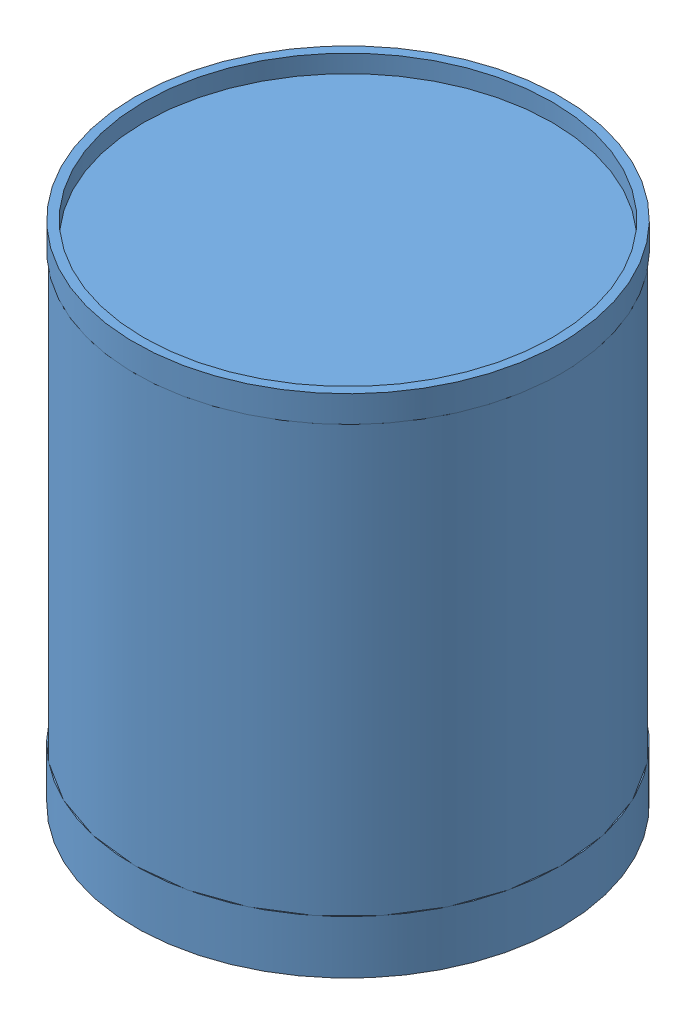
SolidWorks assembly ConceptAssem_2, configuration Free. Lengths in mm.
Overall size (1219.2 1447.8 1219.2).
21 component instances, 5 part files, 67 mates.
Components (placement in the parent):
- Case-1: Case [Default] x (1 0 0) z (0 1 0)
- RotatingStand-1: RotatingStand [Default] at (0 25.4 0) x (1 0 0) z (0 1 0)
- TopSpin_Lower-1: TopSpin_Lower [Default] at (0 152.4 0) x (0.999984 0 -0.005596) z (0 1 0)
- TopSpin_Upper-1: TopSpin_Upper [Default] at (0 266.7 57.1491) x (0.996384 0 0.084968) z (0 1 0)
- SlotGuide-1: SlotGuide [Default] at (0 254 -4.0566) x (-1 0 0) z (0 -1 0)
- SlotGuide-3: SlotGuide [Default] at (0 358.4222 52.8867) x (-1 0 0) z (0 -1 0)
- TopSpin_Upper-3: TopSpin_Upper [Default] at (0 371.1222 114.0924) x (0.999041 0 0.043775) z (0 1 0)
- TopSpin_Upper-5: TopSpin_Upper [Default] at (0 475.5444 171.1877) x (0.998053 0 0.062371) z (0 1 0)
- SlotGuide-5: SlotGuide [Default] at (0 462.8444 109.9819) x (-1 0 0) z (0 -1 0)
- TopSpin_Upper-6: TopSpin_Upper [Default] at (0 579.9667 228.2264) x (0.999167 0 0.040797) z (0 1 0)
- SlotGuide-6: SlotGuide [Default] at (0 567.2667 167.0207) x (-1 0 0) z (0 -1 0)
- TopSpin_Upper-7: TopSpin_Upper [Default] at (0 684.3889 285.3288) x (0.995816 0 0.091386) z (0 1 0)
- SlotGuide-7: SlotGuide [Default] at (0 671.6889 224.1231) x (-1 0 0) z (0 -1 0)
- TopSpin_Upper-8: TopSpin_Upper [Default] at (0 788.8111 342.2397) x (0.999995 0 -0.003028) z (0 1 0)
- SlotGuide-8: SlotGuide [Default] at (0 776.1111 281.0339) x (-1 0 0) z (0 -1 0)
- TopSpin_Upper-9: TopSpin_Upper [Default] at (0 893.2333 399.3894) x (0.999082 0 0.042846) z (0 1 0)
- SlotGuide-9: SlotGuide [Default] at (0 880.5333 338.1837) x (-1 0 0) z (0 -1 0)
- TopSpin_Upper-10: TopSpin_Upper [Default] at (0 997.6556 456.4869) x (0.998156 0 -0.060698) z (0 1 0)
- SlotGuide-10: SlotGuide [Default] at (0 984.9556 395.2812) x (-1 0 0) z (0 -1 0)
- TopSpin_Upper-11: TopSpin_Upper [Default] at (0 1102.0778 513.5315) x (0.999981 0 0.006194) z (0 1 0)
- SlotGuide-11: SlotGuide [Default] at (0 1089.3778 452.3258) x (-1 0 0) z (0 -1 0)
Mates (geometry in assembly coordinates):
- InPlace1: in place: plane of Case-1 through (0 0 0) normal (0 1 0); moOrthogonalPlaneRef_w of Case-1 through (0 0 0) normal (0 0 -1); plane of Case-1 through (0 0 0) normal (1 0 0); unknown of Case-1
- Coincident1: coincident aligned: 
- Coincident2: coincident aligned: plane of Part1^ConceptAssem_2-1 through (0 0 0) normal (0 0 -1)
- Coincident3: coincident anti-aligned: plane of Part1^ConceptAssem_2-1 through (0 0 0) normal (1 0 0)
- InPlace2: in place: plane of Case-1 through (0 25.4 0) normal (0 1 0); plane of RotatingStand-1 through (0 25.4 0) normal (0 1 0); plane of Case-1 through (0 25.4 0) normal (0 1 0); plane of RotatingStand-1 through (0 25.4 0) normal (0 0 -1); plane of Case-1 through (0 25.4 0) normal (0 1 0); plane of RotatingStand-1 through (0 25.4 0) normal (1 0 0); plane of Case-1 through (0 25.4 0) normal (0 1 0); unknown of RotatingStand-1
- Coincident4: coincident: plane of Case-1; plane of RotatingStand-1
- Coincident5: coincident: moOrthogonalPlaneRef_w of Case-1 through (0 25.4 0) normal (0 0 -1); plane of Part2^ConceptAssem_2-1 through (0 25.4 0) normal (0 0 -1)
- Coincident6: coincident: moOrthogonalPlaneRef_w of Case-1 through (0 25.4 0) normal (-1 0 0); plane of Part2^ConceptAssem_2-1 through (0 25.4 0) normal (1 0 0)
- InPlace3: in place: plane of RotatingStand-1 through (0 152.4 0) normal (0 1 0); plane of ? through (0 152.4 0) normal (0 1 0); plane of RotatingStand-1 through (0 152.4 0) normal (0 1 0); plane of ? through (0 152.4 0) normal (0 0 -1); plane of RotatingStand-1 through (0 152.4 0) normal (0 1 0); plane of ? through (0 152.4 0) normal (1 0 0); plane of RotatingStand-1 through (0 152.4 0) normal (0 1 0); unknown of ?
- Coincident7: coincident aligned: plane of RotatingStand-1; plane of TopSpin_Lower-1
- Coincident8: coincident aligned: moOrthogonalPlaneRef_w of RotatingStand-1 through (0 152.4 0) normal (0 0 -1); plane of TopSpin_Lower-1
- Coincident9: coincident anti-aligned: moOrthogonalPlaneRef_w of RotatingStand-1 through (0 152.4 0) normal (-1 0 0); plane of TopSpin_Lower-1
- InPlace4: in place: plane of RotatingStand-1 through (0 254 0) normal (0 -1 0); plane of ? through (0 254 0) normal (0 -1 0); plane of RotatingStand-1 through (0 254 0) normal (0 -1 0); plane of ? through (0 254 0) normal (0 0 -1); plane of RotatingStand-1 through (0 254 0) normal (0 -1 0); plane of ? through (0 254 0) normal (-1 0 0); plane of RotatingStand-1 through (0 254 0) normal (0 -1 0); unknown of ?
- Coincident11: coincident aligned: plane of RotatingStand-1; plane of SlotGuide-1
- Coincident12: coincident aligned: moOrthogonalPlaneRef_w of RotatingStand-1 through (0 254 0) normal (0 0 -1); plane of Part4^ConceptAssem_2-1 through (0 254 0) normal (0 0 -1)
- Coincident13: coincident anti-aligned: moOrthogonalPlaneRef_w of RotatingStand-1 through (0 254 0) normal (1 0 0); plane of Part4^ConceptAssem_2-1 through (0 254 0) normal (-1 0 0)
- Coincident15: coincident anti-aligned: plane of RotatingStand-1 through (0 266.7 0) normal (0 1 0); plane of TopSpin_Upper-1 through (0 266.7 57.1491) normal (0 -1 0)
- Concentric1: concentric anti-aligned: cylinder of RotatingStand-1 through (0 152.4 0) axis (0 -1 0) radius 12.7; cylinder of TopSpin_Lower-1 through (0 103.779 0) axis (0 1 0) radius 12.7
- Coincident16: coincident anti-aligned: plane of RotatingStand-1 through (0 152.4 0) normal (0 1 0); plane of TopSpin_Lower-1 through (0 152.4 0) normal (0 -1 0)
- Coincident56: coincident anti-aligned: plane of RotatingStand-1 through (0 25.4 0) normal (1 0 0); plane of SlotGuide-10 through (0 984.9556 395.2812) normal (-1 0 0)
- Coincident18: coincident aligned: plane of RotatingStand-1 through (0 266.7 0) normal (0 1 0); plane of SlotGuide-1 through (0 266.7 -4.0566) normal (0 1 0)
- Coincident21: coincident: point of TopSpin_Lower-1; plane of SlotGuide-1 through (0 254 57.1491) normal (0 0 -1)
- Concentric2: concentric anti-aligned: cylinder of TopSpin_Upper-1 through (0 236.0395 57.1491) axis (0 1 0) radius 6.35; cylinder of SlotGuide-1 through (0 323.4961 57.1491) axis (0 -1 0) radius 6.35
- Concentric4: concentric anti-aligned: cylinder of SlotGuide-3 through (0 427.9183 114.0924) axis (0 -1 0) radius 6.35; cylinder of TopSpin_Upper-3 through (0 340.4617 114.0924) axis (0 1 0) radius 6.35
- Coincident26: coincident anti-aligned: plane of RotatingStand-1 through (0 371.1222 0) normal (0 1 0); plane of TopSpin_Upper-3 through (0 371.1222 114.0924) normal (0 -1 0)
- Coincident63: coincident anti-aligned: plane of RotatingStand-1 through (0 25.4 0) normal (1 0 0); plane of SlotGuide-3 through (0 358.4222 52.8867) normal (-1 0 0)
- Coincident27: coincident aligned: plane of RotatingStand-1 through (0 371.1222 0) normal (0 1 0); plane of SlotGuide-3 through (0 371.1222 52.8867) normal (0 1 0)
- Coincident30: coincident: point of TopSpin_Upper-1; plane of SlotGuide-3 through (0 358.4222 114.0924) normal (0 0 -1)
- Concentric6: concentric anti-aligned: cylinder of TopSpin_Upper-5 through (0 444.8839 171.1877) axis (0 1 0) radius 6.35; cylinder of SlotGuide-5 through (0 532.3406 171.1877) axis (0 -1 0) radius 6.35
- Coincident32: coincident anti-aligned: plane of RotatingStand-1 through (0 475.5444 0) normal (0 1 0); plane of TopSpin_Upper-5 through (0 475.5444 171.1877) normal (0 -1 0)
- Coincident62: coincident anti-aligned: plane of RotatingStand-1 through (0 25.4 0) normal (1 0 0); plane of SlotGuide-5 through (0 462.8444 109.9819) normal (-1 0 0)
- Coincident33: coincident aligned: plane of RotatingStand-1 through (0 475.5444 0) normal (0 1 0); plane of SlotGuide-5 through (0 475.5444 109.9819) normal (0 1 0)
- Coincident34: coincident: point of TopSpin_Upper-3; plane of SlotGuide-5 through (0 462.8444 171.1877) normal (0 0 -1)
- Concentric7: concentric anti-aligned: cylinder of TopSpin_Upper-6 through (0 549.3062 228.2264) axis (0 1 0) radius 6.35; cylinder of SlotGuide-6 through (0 636.7628 228.2264) axis (0 -1 0) radius 6.35
- Coincident61: coincident anti-aligned: plane of RotatingStand-1 through (0 25.4 0) normal (1 0 0); plane of SlotGuide-6 through (0 567.2667 167.0207) normal (-1 0 0)
- Coincident36: coincident anti-aligned: plane of RotatingStand-1 through (0 579.9667 0) normal (0 1 0); plane of TopSpin_Upper-6 through (0 579.9667 228.2264) normal (0 -1 0)
- Coincident37: coincident aligned: plane of RotatingStand-1 through (0 579.9667 0) normal (0 1 0); plane of SlotGuide-6 through (0 579.9667 167.0207) normal (0 1 0)
- Coincident38: coincident: point of TopSpin_Upper-5; plane of SlotGuide-6 through (0 567.2667 228.2264) normal (0 0 -1)
- Concentric8: concentric anti-aligned: cylinder of TopSpin_Upper-7 through (0 653.7284 285.3288) axis (0 1 0) radius 6.35; cylinder of SlotGuide-7 through (0 741.185 285.3288) axis (0 -1 0) radius 6.35
- Coincident60: coincident anti-aligned: plane of RotatingStand-1 through (0 25.4 0) normal (1 0 0); plane of SlotGuide-7 through (0 671.6889 224.1231) normal (-1 0 0)
- Coincident40: coincident anti-aligned: plane of RotatingStand-1 through (0 684.3889 0) normal (0 1 0); plane of TopSpin_Upper-7 through (0 684.3889 285.3288) normal (0 -1 0)
- Coincident41: coincident aligned: plane of RotatingStand-1 through (0 684.3889 0) normal (0 1 0); plane of SlotGuide-7 through (0 684.3889 224.1231) normal (0 1 0)
- Coincident42: coincident: point of TopSpin_Upper-6; plane of SlotGuide-7 through (0 671.6889 285.3288) normal (0 0 -1)
- Concentric9: concentric anti-aligned: cylinder of TopSpin_Upper-8 through (0 758.1506 342.2397) axis (0 1 0) radius 6.35; cylinder of SlotGuide-8 through (0 845.6072 342.2397) axis (0 -1 0) radius 6.35
- Coincident59: coincident anti-aligned: plane of RotatingStand-1 through (0 25.4 0) normal (1 0 0); plane of SlotGuide-8 through (0 776.1111 281.0339) normal (-1 0 0)
- Coincident44: coincident anti-aligned: plane of RotatingStand-1 through (0 788.8111 0) normal (0 1 0); plane of TopSpin_Upper-8 through (0 788.8111 342.2397) normal (0 -1 0)
- Coincident45: coincident aligned: plane of RotatingStand-1 through (0 788.8111 0) normal (0 1 0); plane of SlotGuide-8 through (0 788.8111 281.0339) normal (0 1 0)
- Coincident46: coincident: point of TopSpin_Upper-7; plane of SlotGuide-8 through (0 776.1111 342.2397) normal (0 0 -1)
- Concentric10: concentric anti-aligned: cylinder of TopSpin_Upper-9 through (0 862.5728 399.3894) axis (0 1 0) radius 6.35; cylinder of SlotGuide-9 through (0 950.0295 399.3894) axis (0 -1 0) radius 6.35
- Coincident58: coincident anti-aligned: plane of RotatingStand-1 through (0 25.4 0) normal (1 0 0); plane of SlotGuide-9 through (0 880.5333 338.1837) normal (-1 0 0)
- Coincident48: coincident anti-aligned: plane of RotatingStand-1 through (0 893.2333 0) normal (0 1 0); plane of TopSpin_Upper-9 through (0 893.2333 399.3894) normal (0 -1 0)
- Coincident49: coincident aligned: plane of RotatingStand-1 through (0 893.2333 0) normal (0 1 0); plane of SlotGuide-9 through (0 893.2333 338.1837) normal (0 1 0)
- Coincident50: coincident: point of TopSpin_Upper-8; plane of SlotGuide-9 through (0 880.5333 399.3894) normal (0 0 -1)
- Concentric11: concentric anti-aligned: cylinder of TopSpin_Upper-10 through (0 966.995 456.4869) axis (0 1 0) radius 6.35; cylinder of SlotGuide-10 through (0 1054.4517 456.4869) axis (0 -1 0) radius 6.35
- Coincident57: coincident anti-aligned: plane of RotatingStand-1 through (0 25.4 0) normal (1 0 0); plane of SlotGuide-9 through (0 880.5333 338.1837) normal (-1 0 0)
- Coincident52: coincident anti-aligned: plane of RotatingStand-1 through (0 997.6556 0) normal (0 1 0); plane of TopSpin_Upper-10 through (0 997.6556 456.4869) normal (0 -1 0)
- Coincident53: coincident aligned: plane of RotatingStand-1 through (0 997.6556 0) normal (0 1 0); plane of SlotGuide-10 through (0 997.6556 395.2812) normal (0 1 0)
- Coincident54: coincident: point of TopSpin_Upper-9; plane of SlotGuide-10 through (0 984.9556 456.4869) normal (0 0 -1)
- Coincident55: coincident anti-aligned: plane of RotatingStand-1 through (0 25.4 0) normal (1 0 0); plane of SlotGuide-1 through (0 254 -4.0557) normal (-1 0 0)
- Coincident64: coincident anti-aligned: plane of RotatingStand-1 through (0 25.4 0) normal (1 0 0); plane of SlotGuide-1 through (0 254 -4.0566) normal (-1 0 0)
- Concentric12: concentric aligned: cylinder of Case-1 through (0 50.8 0) axis (0 -1 0) radius 25.4; cylinder of RotatingStand-1 through (0 38.1 0) axis (0 -1 0) radius 25.4
- Coincident65: coincident anti-aligned: plane of Case-1 through (0 25.4 0) normal (0 1 0); plane of RotatingStand-1 through (0 25.4 0) normal (0 -1 0)
- Concentric13: concentric anti-aligned: cylinder of TopSpin_Upper-11 through (0 1071.4173 513.5315) axis (0 1 0) radius 6.35; cylinder of SlotGuide-11 through (0 1158.8739 513.5315) axis (0 -1 0) radius 6.35
- Coincident66: coincident anti-aligned: plane of RotatingStand-1 through (0 25.4 0) normal (1 0 0); plane of SlotGuide-11 through (0 1089.3778 452.3258) normal (-1 0 0)
- Coincident67: coincident anti-aligned: plane of RotatingStand-1 through (0 1102.0778 0) normal (0 1 0); plane of TopSpin_Upper-11 through (0 1102.0778 513.5315) normal (0 -1 0)
- Coincident68: coincident aligned: plane of RotatingStand-1 through (0 1102.0778 0) normal (0 1 0); plane of SlotGuide-11 through (0 1102.0778 452.3258) normal (0 1 0)
- Coincident69: coincident: point of TopSpin_Upper-10; plane of SlotGuide-11 through (0 1089.3778 513.5315) normal (0 0 -1)
